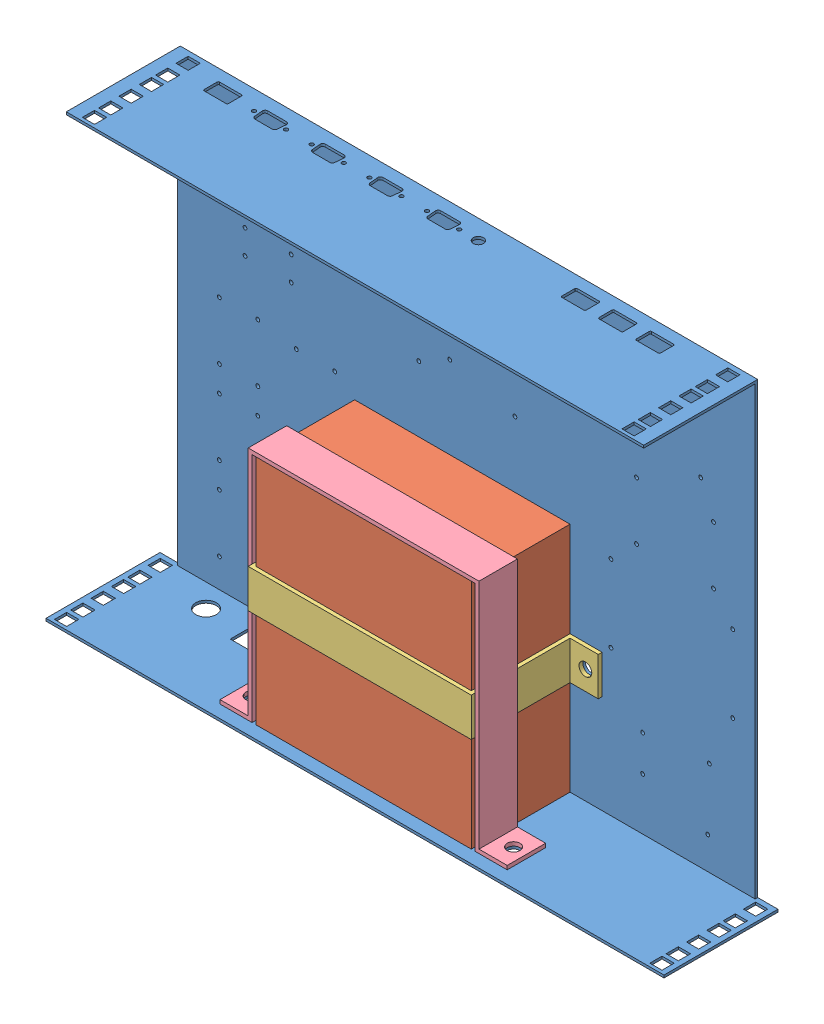
SolidWorks assembly Assem2, configuration Default. Lengths in mm.
Overall size (482 352 88.9).
4 component instances, 4 part files, 9 mates.
Components (placement in the parent):
- Tray fix-1: Tray fix [Default] at (-140.6124 -26.842 47.9853) size (482 352 88.9)
- Battery-1: Battery [Default] at (-227.8124 -19.842 49.9853) size (168 181 77)
- Battery strap 77mm high-1: Battery strap 77mm high [Default] at (-143.8124 -123.842 49.9853) x (-1 0 0) z (0 1 0) size (218 80 30)
- Battery strap 181mm long-1: Battery strap 181mm long [Default] at (-143.8124 -200.842 96.9853) size (224 184 30)
Mates (geometry in assembly coordinates):
- Coincident1: coincident anti-aligned: plane of Tray fix-1 through (-140.6124 -26.842 49.9853) normal (0 0 1); plane of Battery-1 through (-227.8124 -19.842 49.9853) normal (0 0 -1)
- Coincident2: coincident anti-aligned: plane of Tray fix-1 through (-140.6124 -200.842 47.9853) normal (0 1 0); plane of Battery-1 through (-227.8124 -200.842 126.9853) normal (0 -1 0)
- Distance1: distance = 138 mm: line of Tray fix-1 through (-365.8124 147.158 49.9853) axis (0 -1 0); plane of Battery-1 through (-227.8124 -19.842 126.9853) normal (-1 0 0)
- Coincident6: coincident anti-aligned: plane of Battery-1 through (-227.8124 -19.842 126.9853) normal (0 0 1); plane of Battery strap 77mm high-1 through (-59.8124 -93.842 126.9853) normal (0 0 -1)
- Coincident7: coincident anti-aligned: plane of Battery-1 through (-227.8124 -19.842 126.9853) normal (-1 0 0); plane of Battery strap 77mm high-1 through (-227.8124 -93.842 126.9853) normal (1 0 0)
- Distance3: distance = 77 mm anti-aligned: plane of Battery strap 77mm high-1 through (-143.8124 -123.842 49.9853) normal (0 -1 0); plane of Tray fix-1 through (-140.6124 -200.842 47.9853) normal (0 1 0)
- Coincident15: coincident anti-aligned: plane of Tray fix-1 through (-140.6124 -200.842 47.9853) normal (0 1 0); plane of Battery strap 181mm long-1 through (-255.8124 -200.842 126.9853) normal (0 -1 0)
- Concentric4: concentric anti-aligned: cylinder of Tray fix-1 through (-245.8124 149.159 111.9853) axis (0 -1 0) radius 5; cylinder of Battery strap 181mm long-1 through (-245.8124 -227.842 111.9853) axis (0 1 0) radius 5
- Concentric5: concentric anti-aligned: cylinder of Tray fix-1 through (-41.8124 149.159 111.9853) axis (0 -1 0) radius 5; circle of Battery strap 181mm long-1
